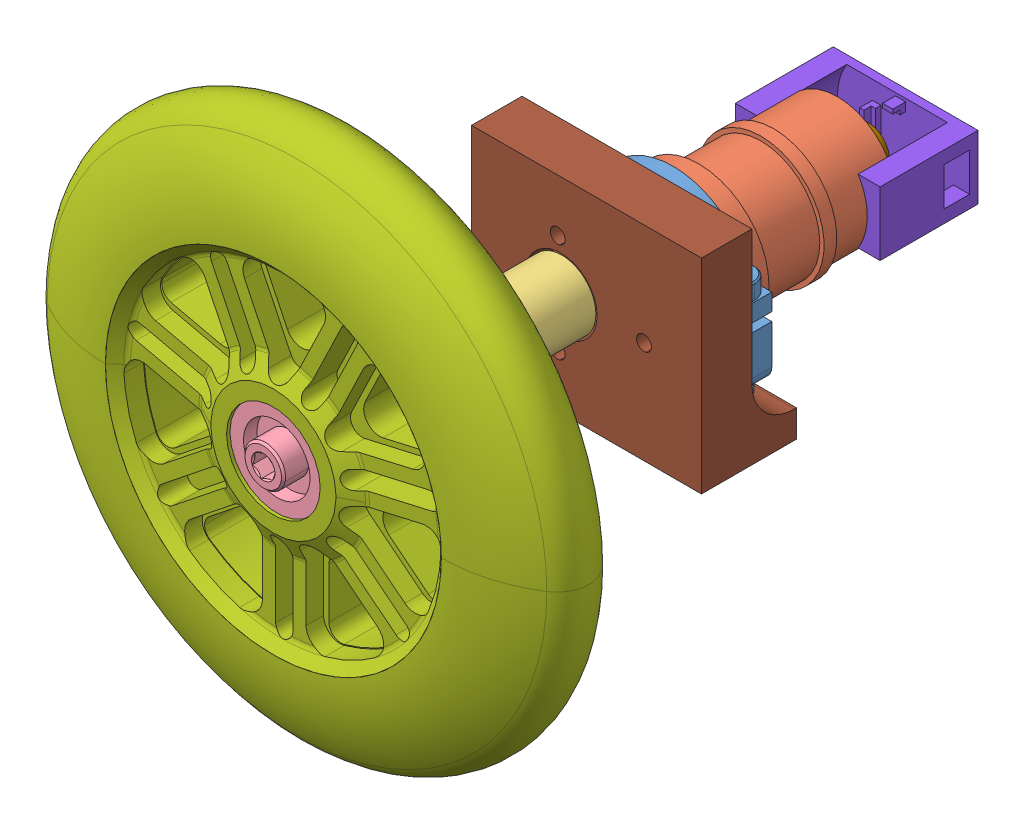
SolidWorks assembly DriveAssemblyLeft, configuration Default. Lengths in mm.
Overall size (124.46 124.46 144.88).
11 component instances, 11 part files, 26 mates.
Components (placement in the parent):
- 1400-0032-0032 assembly.STEP-1: 1400-0032-0032 assembly.STEP [Default] at (6.581 -3.5947 -1.114) size (42.17 43 8)
- Motor-2: Motor [Default] at (-2.6241 5.961 7.9343) x (0 0 -1) z (0 1 0) size (70.6 33 33)
- Coupler-1: Coupler [Default] at (-8.6241 5.961 25.3343) x (0 0 1) z (-0.88407 -0.467355 0) size (22.5 16 16)
- 595630 assembly.STEP-1: 595630 assembly.STEP [Default] at (-50.3353 -14.4315 51.5475) x (-0.997959 -0.063851 0) z (-0.063851 0.997959 0) size (25.39 31.39 25.39)
- 545579 assembly.STEP-1: 545579 assembly.STEP [Default] at (19.7418 -41.3992 66.5368) x (0.750814 -0.660514 0) z (0.660514 0.750814 0) size (20.57 9.61 20.57)
- 1602-0032-0250 assembly.STEP-1: 1602-0032-0250 assembly.STEP [Default] at (-40.6325 25.9608 25.7882) x (-1 0 0) z (0 -1 0) size (38 7 33.35)
- 3608-0001-0125 assembly.STEP-1: 3608-0001-0125 assembly.STEP [Default] at (-21.1121 15.7426 69.8072) size (124.46 124.46 23.93)
- Encoder_BracketMount_V2-1: Encoder_BracketMount_V2 [Default] at (-2.6241 5.961 -58.6657) x (0 1 0) z (0 0 1) size (15 34 23)
- Encoder_MagnetMount_V2-1: Encoder_MagnetMount_V2 [Default] at (-2.6241 5.961 -49.8657) x (-1 0 0) z (0 0 -1) size (10 10 5)
- 634060-1: 634060 [Default] at (-8.6241 5.961 55.6343) x (0 -1 0) z (1 0 0) size (5.71 25.4 6.34)
- MotorMount-1: MotorMount [Default] at (-2.6241 5.961 11.1093) size (54 48 23.2)
Mates (geometry in assembly coordinates):
- Concentric1: concentric anti-aligned: cylinder of 1400-0032-0032 assembly.STEP-1 through (-2.6241 5.961 1.9343) axis (0 0 -1) radius 16; cylinder of Motor-2 through (-2.6241 5.961 7.9343) axis (0 0 1) radius 16.5
- Width1: width: plane of Motor-2 through (-2.6241 5.961 7.9343) normal (0 0 1); plane of Motor-2 through (-2.6241 5.961 -12.0657) normal (0 0 -1); plane of 1400-0032-0032 assembly.STEP-1 through (-2.6241 5.961 -6.0657) normal (0 0 -1); plane of 1400-0032-0032 assembly.STEP-1 through (-2.6241 5.961 1.9343) normal (0 0 1)
- Parallel1: parallel aligned: plane of 1400-0032-0032 assembly.STEP-1 through (-21.6241 -18.039 1.9343) normal (-1 0 0); plane of Motor-2 through (-10.1241 5.961 12.4343) normal (-1 0 0)
- Concentric2: concentric anti-aligned: cylinder of Motor-2 through (-8.6241 5.961 20.4343) axis (0 0 1) radius 2.5; cylinder of Coupler-1 through (-8.6241 5.961 36.5843) axis (0 0 -1) radius 2.5
- Concentric3: concentric anti-aligned: cylinder of 595630 assembly.STEP-1 through (-8.6241 5.961 59.8045) axis (0 0 -1) radius 6.35; cylinder of 545579 assembly.STEP-1 through (-8.6241 5.961 52.8195) axis (0 0 1) radius 6.35
- Concentric4: concentric aligned: cylinder of 595630 assembly.STEP-1 through (-9.2485 15.7201 54.0895) axis (0 0 1) radius 1.778; circle of 545579 assembly.STEP-1
- Coincident5: coincident anti-aligned: plane of 595630 assembly.STEP-1 through (-8.6241 5.961 52.8195) normal (0 0 -1); plane of 545579 assembly.STEP-1 through (-13.5036 5.6488 52.8195) normal (0 0 1)
- Coincident6: coincident aligned: plane of 1400-0032-0032 assembly.STEP-1 through (10.3759 -18.039 1.9343) normal (0 -1 0); plane of 1602-0032-0250 assembly.STEP-1 through (10.3759 -18.039 37.7968) normal (0 -1 0)
- Concentric5: concentric aligned: cylinder of Coupler-1 through (-8.6241 5.961 25.3343) axis (0 0 1) radius 3.175; cylinder of 1602-0032-0250 assembly.STEP-1 through (-8.6241 5.961 40.0343) axis (0 0 1) radius 3.175
- Concentric8: concentric aligned: cylinder of 1602-0032-0250 assembly.STEP-1 through (-8.6241 5.961 62.7573) axis (0 0 -1) radius 5.35; cylinder of 3608-0001-0125 assembly.STEP-1 through (-8.6241 5.961 81.8263) axis (0 0 -1) radius 9.5758
- Concentric9: concentric aligned: cylinder of 595630 assembly.STEP-1 through (-8.6241 5.961 74.1763) axis (0 0 1) radius 10.9855; cylinder of 3608-0001-0125 assembly.STEP-1 through (-8.6241 5.961 74.7626) axis (0 0 1) radius 11
- Coincident10: coincident anti-aligned: plane of 595630 assembly.STEP-1 through (-8.6241 5.961 57.8995) normal (0 0 1); plane of 3608-0001-0125 assembly.STEP-1 through (6.0589 5.961 57.8995) normal (0 0 -1)
- Parallel3: parallel anti-aligned: plane of 1400-0032-0032 assembly.STEP-1 through (10.3759 -18.039 1.9343) normal (0 -1 0); plane of Encoder_BracketMount_V2-1 through (-2.6241 13.461 -41.6657) normal (0 1 0)
- Concentric11: concentric anti-aligned: cylinder of Motor-2 through (-2.6241 5.961 7.9343) axis (0 0 1) radius 13.85; cylinder of Encoder_BracketMount_V2-1 through (-2.6241 5.961 -41.6657) axis (0 0 -1) radius 14
- Coincident17: coincident aligned: plane of Motor-2 through (-2.6241 5.961 -44.6657) normal (0 0 -1); plane of Encoder_BracketMount_V2-1 through (-2.6241 5.961 -44.6657) normal (0 0 -1)
- Coincident18: coincident anti-aligned: plane of Motor-2 through (-2.6241 5.961 -46.8657) normal (0 0 -1); plane of Encoder_MagnetMount_V2-1 through (-2.6241 5.961 -46.8657) normal (0 0 1)
- Concentric12: concentric anti-aligned: cylinder of Motor-2 through (-2.6241 5.961 7.9343) axis (0 0 1) radius 1.15; cylinder of Encoder_MagnetMount_V2-1 through (-2.6241 5.961 -46.8657) axis (0 0 -1) radius 1.25
- Distance8: distance = 22.225 mm anti-aligned: plane of 595630 assembly.STEP-1 through (-8.6241 5.961 58.8093) normal (0 0 -1); plane of Coupler-1 through (-8.6241 5.961 36.5843) normal (0 0 1)
- Coincident22: coincident anti-aligned: plane of Motor-2 through (-2.6241 5.961 20.4343) normal (0 0 1); plane of Coupler-1 through (-8.6241 5.961 20.4343) normal (0 0 -1)
- Coincident23: coincident anti-aligned: plane of Coupler-1 through (-8.6241 5.961 30.2343) normal (0 0 1); plane of 634060-1 through (-8.6241 5.961 30.2343) normal (0 0 -1)
- Concentric14: concentric aligned: cylinder of Coupler-1 through (-8.6241 5.961 25.3343) axis (0 0 1) radius 3.175; cylinder of 634060-1 through (-8.6241 5.961 23.8843) axis (0 0 1) radius 3.1712
- Distance9: distance = 42.8625 mm aligned: plane of 1602-0032-0250 assembly.STEP-1 through (-8.6241 5.961 44.7968) normal (0 0 1); plane of 1400-0032-0032 assembly.STEP-1 through (-2.6241 5.961 1.9343) normal (0 0 1)
- Parallel7: parallel aligned: plane of 1602-0032-0250 assembly.STEP-1 through (-27.6241 -8.7963 37.7968) normal (-1 0 0); plane of 3608-0001-0125 assembly.STEP-1 through (-15.0249 -7.3304 81.8263) normal (-1 0 0)
- Coincident24: coincident anti-aligned: plane of Motor-2 through (-2.6241 5.961 7.9343) normal (0 0 1); plane of MotorMount-1 through (-2.6241 5.961 7.9343) normal (0 0 -1)
- Concentric15: concentric anti-aligned: cylinder of Motor-2 through (-8.6241 5.961 20.4343) axis (0 0 1) radius 5; cylinder of MotorMount-1 through (-8.6241 5.961 14.2843) axis (0 0 -1) radius 8.5
- Coincident25: coincident aligned: plane of 1602-0032-0250 assembly.STEP-1 through (10.3759 -18.039 37.7968) normal (0 -1 0); plane of MotorMount-1 through (-26.6241 -18.039 14.2843) normal (0 -1 0)
